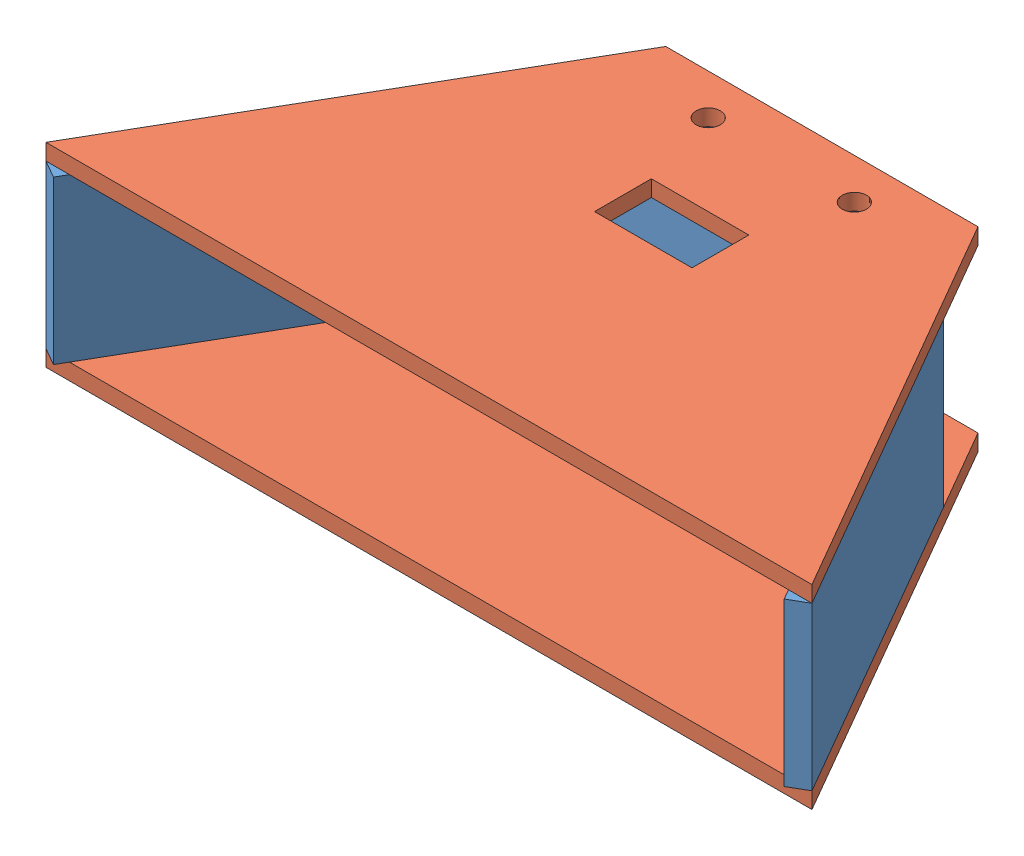
SolidWorks assembly Assemblage_Sharp, configuration Défaut. Lengths in mm.
Overall size (94.33 24 49.64).
3 component instances, 2 part files, 4 mates.
Components (placement in the parent):
- CarterSharp-1: CarterSharp [Défaut] at (-51.1745 23.3146 -14.8205) size (94.33 20 49.64)
- ToitSharp-1: ToitSharp [Défaut] at (-52.0839 33.3146 14.3122) size (94.33 2 48.39)
- ToitSharp-2: ToitSharp [Défaut] at (-52.0839 11.3146 14.3122) size (94.33 2 48.39)
Mates (geometry in assembly coordinates):
- Coïncidente1: coincident anti-aligned: plane of CarterSharp-1 through (-76.1745 33.3146 -9.8205) normal (0 1 0); plane of ToitSharp-1 through (-31.948 33.3146 -24.8205) normal (0 -1 0)
- Coïncidente2: coincident aligned: plane of CarterSharp-1 through (-64.1745 13.3146 -24.8205) normal (0 0 -1); plane of ToitSharp-1 through (-70.401 35.3146 -24.8205) normal (0 0 -1)
- Coaxiale1: concentric: circle of CarterSharp-1; circle of ToitSharp-2
- Coïncidente4: coincident aligned: circle of CarterSharp-1; circle of ToitSharp-2
